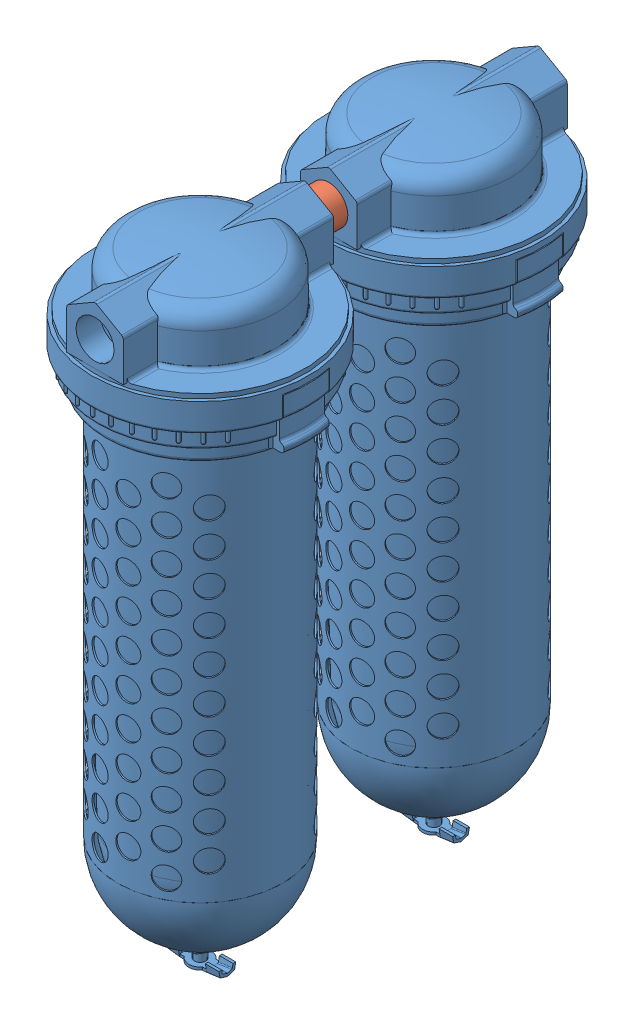
SolidWorks assembly ReadingTech_4P-150-P04-DCP, configuration Default. Lengths in mm.
Overall size (121.86 350.16 252.73).
3 component instances, 2 part files, 3 mates.
Components (placement in the parent):
- ReadingTech_3P-150-P04-P-1: ReadingTech_3P-150-P04-P [Default] at (2.8272 -210.8865 -13.1093) size (121.86 350.16 121.67)
- ReadingTech_3P-150-P04-P-2: ReadingTech_3P-150-P04-P [Default] at (2.8272 -210.8865 -144.1733) size (121.86 350.16 121.67)
- ReadingTech- 90,150cfm_connector_.5in-1: ReadingTech- 90,150cfm_connector_.5in [Default] at (2.8272 174.0505 -72.0373) x (1 0 0) z (0 1 0) size (21.34 13.21 21.34)
Mates (geometry in assembly coordinates):
- Coincident1: coincident anti-aligned: circle of ReadingTech_3P-150-P04-P-2; circle of ReadingTech- 90,150cfm_connector_.5in-1
- Coincident2: coincident aligned: circle of ReadingTech_3P-150-P04-P-1; circle of ReadingTech- 90,150cfm_connector_.5in-1
- Coincident3: coincident aligned: plane of ReadingTech_3P-150-P04-P-1 through (18.7022 182.9405 45.8187) normal (1 0 0); plane of ReadingTech_3P-150-P04-P-2 through (18.7022 182.9405 -85.2453) normal (1 0 0)
